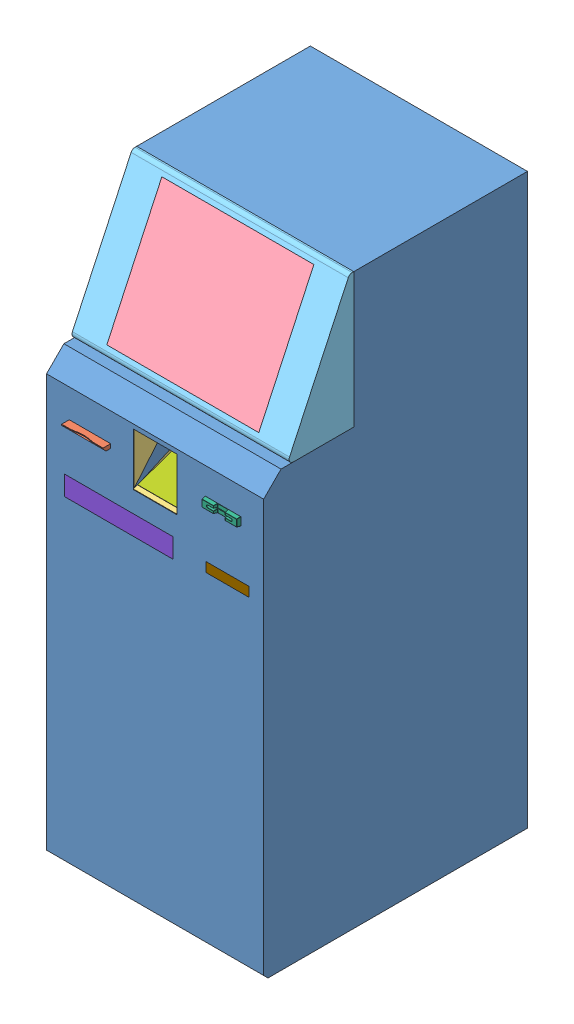
SolidWorks assembly 0StandardConcept17inclined, configuration Default. Lengths in mm.
Overall size (500 1310 624.98).
9 component instances, 9 part files, 25 mates.
Components (placement in the parent):
- Body-1: Body [Default] at (-208.3287 -13.927 -327.7702) size (500 1310 607.53)
- thermal printer-1: thermal printer [Default] at (-108.3287 819.573 -191.2702) size (132 144.55 271.2)
- POS-In-1: POS-In [Default] at (93.6713 938.073 -128.7702) size (104 123.01 101.61)
- 17inch-1: 17inch [Default] at (-133.3287 1005.1268 -200.6596) x (1 0 0) z (0 0.422618 0.906308) size (350 300 10)
- Screen17inclined-1: Screen17inclined [Default] at (-208.3287 986.073 -335.2963) x (0 0 -1) z (1 0 0) size (148.86 310 500)
- XST card reader PI65C-120-GDS-MFR-1: XST card reader PI65C-120-GDS-MFR [Default] at (198.0454 875.5747 -131.3102) size (101.6 25.4 105.37)
- KeypadMetal-1: KeypadMetal [Default] at (41.6713 847.6632 -220.3257) x (1 0 0) z (0 -0.939693 -0.34202) size (133.3 91.1 23.5)
- DispenserShutter-1: DispenserShutter [Default] at (83.3379 721.867 -137.7702) size (250 45 10)
- AcceptorShutter-1: AcceptorShutter [Default] at (258.3379 733.367 -137.7702) size (100 22 10)
Mates (geometry in assembly coordinates):
- Coincident5: coincident aligned: plane of thermal printer-1 through (-108.3287 877.873 -128.7702) normal (0 0 1); plane of assembly through (0 0 -128.7702) normal (0 0 1)
- Parallel2: parallel aligned: plane of Body-1 through (291.6713 986.073 -167.7702) normal (0 1 0); plane of POS-In-1 through (93.6713 938.073 -128.7702) normal (0 1 0)
- Coincident8: coincident aligned: plane of POS-In-1 through (-10.3287 936.073 -128.7702) normal (0 0 1); plane of assembly through (0 0 -128.7702) normal (0 0 1)
- Coincident9: coincident aligned: plane of Body-1 through (-8.3287 936.073 -395.7702) normal (1 0 0); plane of POS-In-1 through (-8.3287 938.073 -128.7702) normal (1 0 0)
- Coincident10: coincident aligned: plane of Body-1 through (-8.3287 936.073 -395.7702) normal (0 -1 0); plane of POS-In-1 through (93.6713 936.073 -128.7702) normal (0 -1 0)
- Coincident11: coincident anti-aligned: plane of Body-1 through (-60.6787 880.573 -395.7702) normal (0 -1 0); plane of thermal printer-1 through (-60.6787 880.573 -128.7702) normal (0 1 0)
- Coincident12: coincident anti-aligned: plane of Body-1 through (-60.6787 880.573 -395.7702) normal (-1 0 0); plane of thermal printer-1 through (-60.6787 871.173 -128.7702) normal (1 0 0)
- Coincident18: coincident anti-aligned: plane of Body-1 through (291.6713 986.073 -335.2963) normal (0 0 1); plane of Screen17inclined-1 through (291.6713 986.073 -335.2963) normal (0 0 -1)
- Width4: width anti-aligned: plane of Screen17inclined-1 through (291.6713 1286.073 -331.667) normal (1 0 0); plane of Screen17inclined-1 through (-208.3287 1286.073 -331.667) normal (-1 0 0); plane of Body-1 through (-208.3287 -13.927 -327.7702) normal (-1 0 0); plane of Body-1 through (291.6713 -13.927 -327.7702) normal (1 0 0)
- Coincident19: coincident anti-aligned: plane of Body-1 through (291.6713 986.073 -167.7702) normal (0 1 0); plane of Screen17inclined-1 through (291.6713 986.073 -196.4377) normal (0 -1 0)
- Coincident20: coincident aligned: plane of 17inch-1 through (-133.3287 1009.353 -191.5965) normal (0 0.422618 0.906308); plane of Screen17inclined-1 through (291.6713 1290.2992 -322.6039) normal (0 0.422618 0.906308)
- Coincident21: coincident anti-aligned: plane of 17inch-1 through (-133.3287 1281.2454 -318.382) normal (-1 0 0); plane of Screen17inclined-1 through (-133.3287 1281.2454 -418.382) normal (1 0 0)
- Coincident22: coincident aligned: line of 17inch-1 through (216.6713 1281.2454 -318.382) axis (-1 0 0); line of Screen17inclined-1 through (216.6713 1281.2454 -318.382) axis (-1 0 0)
- Distance1: distance = 1 mm aligned: plane of XST card reader PI65C-120-GDS-MFR-1 through (248.8445 862.8747 -128.7702) normal (0 0 1); plane of Body-1 through (291.6713 -3.927 -127.7702) normal (0 0 1)
- Coincident24: coincident anti-aligned: plane of Body-1 through (239.3213 884.973 -395.7702) normal (-1 0 0); plane of XST card reader PI65C-120-GDS-MFR-1 through (239.3213 866.1763 -128.7702) normal (1 0 0)
- Distance3: distance = 1 mm aligned: plane of KeypadMetal-1 through (41.6713 849.5426 -219.6416) normal (0 0.939693 0.34202); plane of POS-In-1 through (93.6713 831.8818 -168.1953) normal (0 0.939693 0.34202)
- Width6: width anti-aligned: plane of POS-In-1 through (91.6713 938.073 -128.7702) normal (-1 0 0); plane of POS-In-1 through (-8.3287 938.073 -128.7702) normal (1 0 0); plane of KeypadMetal-1 through (100.2713 837.4206 -224.0537) normal (1 0 0); plane of KeypadMetal-1 through (-16.9287 837.4206 -224.0537) normal (-1 0 0)
- Distance4: distance = 10 mm aligned: plane of KeypadMetal-1 through (-6.8287 821.3071 -136.2177) normal (0 -0.34202 0.939693); plane of POS-In-1 through (-7.5921 815.0679 -127.8468) normal (0 -0.34202 0.939693)
- Coincident33: coincident anti-aligned: plane of Body-1 through (156.7813 884.973 -395.7702) normal (0 -1 0); plane of XST card reader PI65C-120-GDS-MFR-1 through (156.7695 884.973 -128.7702) normal (0 1 0)
- Coincident34: coincident aligned: plane of Body-1 through (291.6713 -3.927 -127.7702) normal (0 0 1); plane of DispenserShutter-1 through (83.3379 721.867 -127.7702) normal (0 0 1)
- Coincident35: coincident anti-aligned: plane of Body-1 through (83.3379 766.867 -395.7702) normal (-1 0 0); plane of DispenserShutter-1 through (83.3379 721.867 -127.7702) normal (1 0 0)
- Coincident36: coincident anti-aligned: plane of Body-1 through (-166.6621 766.867 -395.7702) normal (0 -1 0); plane of DispenserShutter-1 through (83.3379 766.867 -127.7702) normal (0 1 0)
- Coincident37: coincident anti-aligned: plane of Body-1 through (158.3379 755.367 -395.7702) normal (0 -1 0); plane of AcceptorShutter-1 through (258.3379 755.367 -127.7702) normal (0 1 0)
- Coincident38: coincident anti-aligned: plane of Body-1 through (258.3379 733.367 -395.7702) normal (-1 0 0); plane of AcceptorShutter-1 through (258.3379 733.367 -127.7702) normal (1 0 0)
- Coincident39: coincident aligned: plane of Body-1 through (291.6713 -3.927 -127.7702) normal (0 0 1); plane of AcceptorShutter-1 through (258.3379 733.367 -127.7702) normal (0 0 1)
